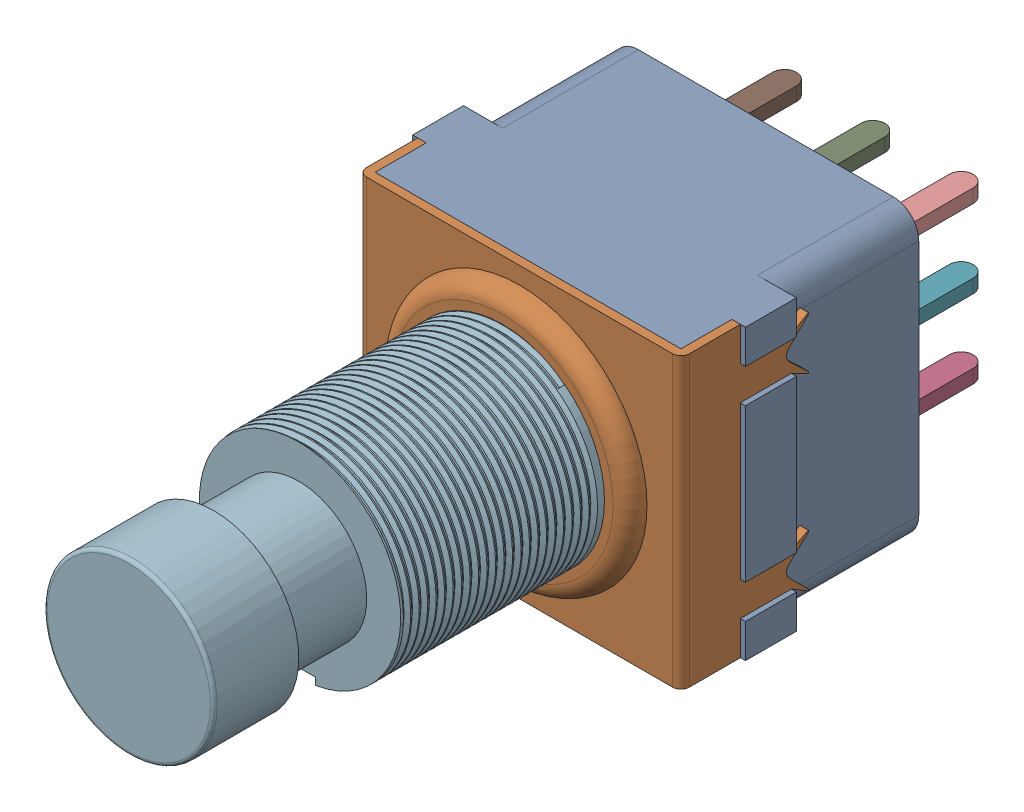
SolidWorks assembly FSW3, configuration Default. Lengths in mm.
Overall size (19.6 17 44.5).
13 component instances, 4 part files, 0 mates.
Components (placement in the parent):
- 3PDT-1: 3PDT [Default] at (130.2994 72.0412 1.27) x (1 0 0) z (0 0 1) size (19.6 17 44.5)
  - 3PDT Body-1: 3PDT Body [Default] at (0 -2.1806 0.7727) size (19.6 17 15)
  - 3PDT Cover-1: 3PDT Cover [Default] at (-0.5 14.8194 11.7727) x (1 0 0) z (0 -1 0) size (19 8.5 17)
  - 3PDT Pin-1: 3PDT Pin [Default] at (7 1.7194 0.7727) x (1 0 0) z (0 1 0) size (4 7 0.8)
  - 3PDT Pin-2: 3PDT Pin [Default] at (12.2 1.7194 0.7727) x (1 0 0) z (0 1 0) size (4 7 0.8)
  - 3PDT Pin-3: 3PDT Pin [Default] at (1.8 1.7194 0.7727) x (1 0 0) z (0 1 0) size (4 7 0.8)
  - 3PDT Pin-4: 3PDT Pin [Default] at (7 6.3194 0.7727) x (1 0 0) z (0 1 0) size (4 7 0.8)
  - 3PDT Pin-5: 3PDT Pin [Default] at (12.2 6.3194 0.7727) x (1 0 0) z (0 1 0) size (4 7 0.8)
  - 3PDT Pin-6: 3PDT Pin [Default] at (1.8 6.3194 0.7727) x (1 0 0) z (0 1 0) size (4 7 0.8)
  - 3PDT Pin-7: 3PDT Pin [Default] at (7 10.9194 0.7727) x (1 0 0) z (0 1 0) size (4 7 0.8)
  - 3PDT Pin-8: 3PDT Pin [Default] at (12.2 10.9194 0.7727) x (1 0 0) z (0 1 0) size (4 7 0.8)
  - 3PDT Pin-9: 3PDT Pin [Default] at (1.8 10.9194 0.7727) x (1 0 0) z (0 1 0) size (4 7 0.8)
  - 3PDT Schalter-1: 3PDT Schalter [Default] at (9 6.3194 28.2727) x (0 -1 0) z (0 0 1) size (12 12.17 22.2)
